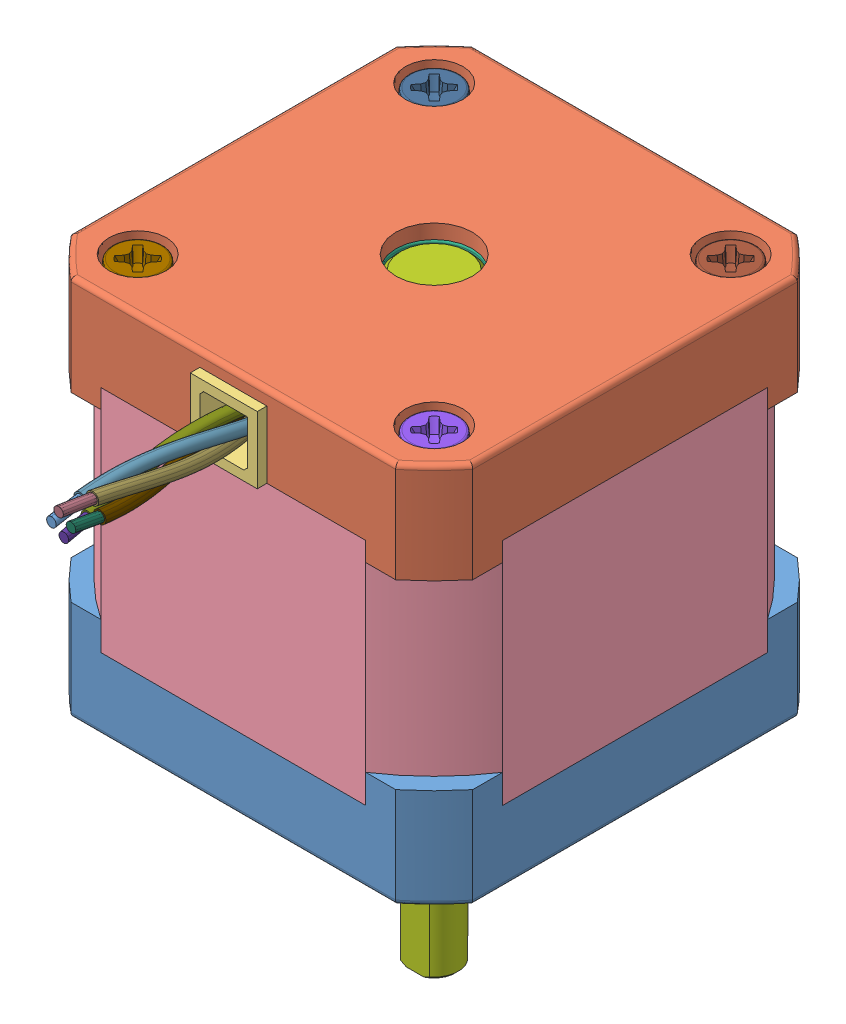
SolidWorks assembly NEMA17 x 40, configuration Default. Lengths in mm.
Overall size (42.05 64.01 60.02).
19 component instances, 19 part files, 0 mates.
Components (placement in the parent):
- Frontplate-1: Frontplate [Default] at (0 10.5 0) size (42.05 12.5 42.05)
- Backplate-1: Backplate [Default] at (0 40 0) size (42.05 10.51 42.05)
- Connenctor-1: Connenctor [Default] at (0 31.5 22) size (7 7 7)
- Housing-1: Housing [Default] at (0 7.5 0) size (42 24 42)
- Bearing dummy-1: Bearing dummy [Default] at (0 4 0) size (22 7.01 22)
- Bearing dummy 01-1: Bearing dummy 01 [Default] at (0 35 0) size (22 7.01 22)
- Core-1: Core [Default] at origin size (30 62.5 30)
- M3x34-Screw-1: M3x34-Screw [Default] at (15.5 37.6 15.5) x (1 0 0) z (0 1 0) size (5.5 5.5 36)
- M3x34-Screw001-1: M3x34-Screw001 [Default] at (-15.5 37.6 15.5) x (1 0 0) z (0 1 0) size (5.5 5.5 36)
- M3x34-Screw002-1: M3x34-Screw002 [Default] at (-15.5 37.6 -15.5) x (1 0 0) z (0 1 0) size (5.5 5.5 36)
- M3x34-Screw003-1: M3x34-Screw003 [Default] at (15.5 37.6 -15.5) x (1 0 0) z (0 1 0) size (5.5 5.5 36)
- Cable-1of4-1: Cable-1of4 [Default] at (0 35 0) size (3.46 3.71 21)
- Copper-1of4-1: Copper-1of4 [Default] at (0 35 0) size (2.79 3.09 24)
- Cable-2of4-1: Cable-2of4 [Default] at (0 35 0) x (0 1 0) z (0 0 1) size (3.46 3.71 21)
- Copper-4of4-1: Copper-4of4 [Default] at (0 35 0) x (0 -1 0) z (0 0 1) size (2.79 3.09 24)
- Cable-3of4-1: Cable-3of4 [Default] at (0 35 0) x (-1 0 0) z (0 0 1) size (3.46 3.71 21)
- Copper-3of4-1: Copper-3of4 [Default] at (0 35 0) x (-1 0 0) z (0 0 1) size (2.79 3.09 24)
- Cable-4of4-1: Cable-4of4 [Default] at (0 35 0) x (0 -1 0) z (0 0 1) size (3.46 3.71 21)
- Copper-2of4-1: Copper-2of4 [Default] at (0 35 0) x (0 1 0) z (0 0 1) size (2.79 3.09 24)
